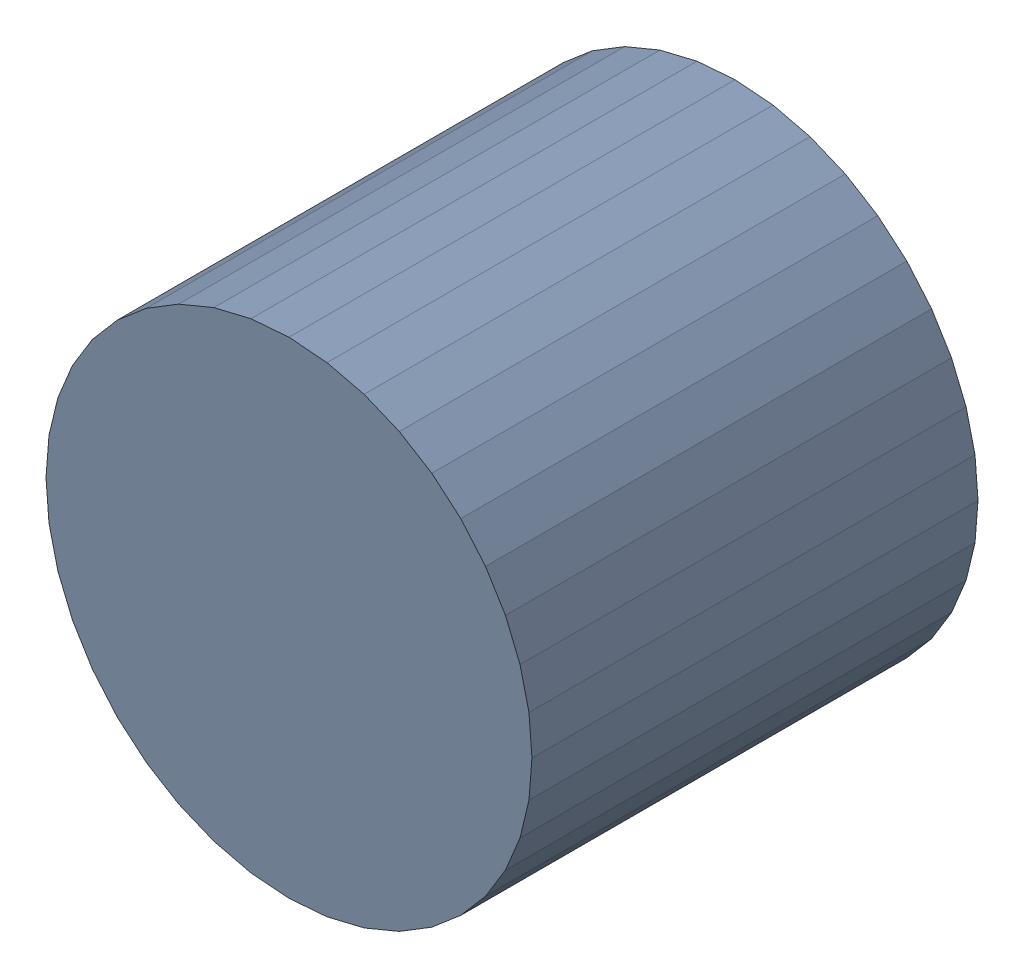
SolidWorks assembly CoutB2Kanaloa_v2.0.0_Power, configuration Default. Lengths in mm.
Overall size (6.32 6.32 5.8).
2 component instances, 1 part files, 0 mates.
Components (placement in the parent):
- 352892112-1: 352892112 [Default] at (75.65 45.95 0) size (6.32 6.32 5.8)
  - Extruded_11-1: Extruded_11 [Default] at origin size (6.32 6.32 5.8)
